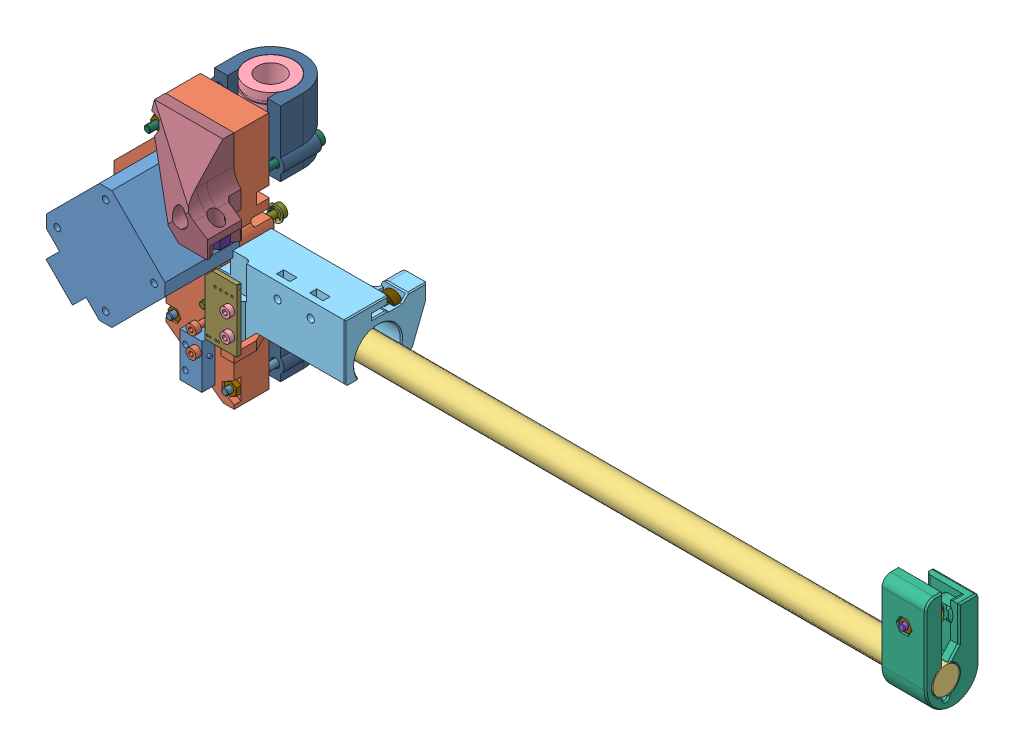
SolidWorks assembly 760, configuration Default. Lengths in mm.
Overall size (372.85 108.5 80.25).
66 component instances, 29 part files, 180 mates.
Components (placement in the parent):
- 561-1: 561 [Default] at (0 0 -40.5115) size (374.33 108.5 5) (hidden)
- 408-1: 408 [Default] at (0 0 14.2385) x (0.707107 0.707107 0) z (0 0 -1) size (50.7 42 57.75)
- 473-1: 473 [Default] at (0 0 -35.5115) size (60.5 108.5 22)
- 402-1: 402 [Default] at (337 -20 -29.4615) x (0 0.998575 0.053361) z (-1 0 0) size (12 12 350)
- 444-1: 444 [Default] at (9.5 13.5 -51.0115) x (0.980494 0 -0.196548) z (0 1 0) size (21 21 30)
- 444-2: 444 [Default] at (9.5 -65 -51.0115) x (0.998608 0 0.052748) z (0 1 0) size (21 21 30)
- 546-1: 546 [Default] at (56.7076 -20 -29.4615) x (0 0 -1) z (0 1 0) size (38 60 36)
- 462-1: 462 [Default] at (337 -20 -29.4615) x (0 -1 0) z (-1 0 0) size (47 24 20)
- 279-1: 279 [Default] at (326.1205 1.9151 -31.2115) x (0.586338 -0.810066 0) z (0 0 1) size (10 10 4)
- 562-1: 562 [Default] at (317 10 -27.9115) x (1 0 0) z (0 1 0) size (319.5 28 5) (hidden)
- 468-1: 468 [Default] at (327 0.7 -42.6615) x (-0.768982 0.639271 0) z (0 0 -1) size (6.75 6.75 25)
- 258-1: 258 [Default] at (327 0.7 -23.4615) x (0.5 -0.866025 0) z (0 0 1) size (6.35 5.5 2.4)
- 279-2: 279 [Default] at (63.5 12.093 -35.0678) x (0 0.271304 -0.962494) z (-1 0 0) size (10 10 4) (hidden)
- 257-1: 257 [Default] at (62 12.5 -36.5115) x (0 -0.745678 0.666307) z (-1 0 0) size (5.7 5.7 15) (hidden)
- 258-2: 258 [Default] at (73.9 12.5 -36.5115) x (0 1 0) z (-1 0 0) size (6.35 5.5 2.4) (hidden)
- 407-1: 407 [Default] at (88.5 12.5 -66.5115) x (0 0 1) z (-1 0 0) size (39.3 20.5 20) (hidden)
- 279-3: 279 [Default] at (63.5 13.116 -67.8792) x (0 -0.41064 0.911797) z (-1 0 0) size (10 10 4) (hidden)
- 492-1: 492 [Default] at (9.5 13.5 -51.0115) x (1 0 0) z (0 1 0) size (33.1 25.5 30)
- 241-1: 241 [Default] at (62 12.5 -66.5115) x (0 0.346036 0.938221) z (-1 0 0) size (5.7 5.7 23) (hidden)
- 258-3: 258 [Default] at (78.9 12.5 -66.5115) x (0 0 1) z (-1 0 0) size (6.35 5.5 2.4) (hidden)
- 443-1: 443 [Default] at (57.7076 -20 -29.4615) x (0 0.269578 -0.962978) z (-1 0 0) size (21 21 57) (hidden)
- 1095-1: 1095 [Default] at (24.2076 -32.9 -17.93) x (-1 0 0) z (0 -1 0) size (7 7.7 2.5)
- 545-1: 545 [Default] at (26.4299 -22.001 -13.4615) size (14.35 28.32 1.85)
- 467-1: 467 [Default] at (84.5 12.5 -44.7865) x (-1 0 0) z (0 0 -1) size (6.75 6.75 20) (hidden)
- 258-4: 258 [Default] at (84.5 12.5 -30.0115) x (0.866025 0.5 0) z (0 0 1) size (6.35 5.5 2.4) (hidden)
- 258-5: 258 [Default] at (72.5 20.1 -46.9115) x (0.866025 -0.5 0) z (0 0 1) size (6.35 5.5 2.4) (hidden)
- 258-6: 258 [Default] at (-10.5 -27.55 -22.5115) x (-0.5 -0.866025 0) z (0 0 1) size (6.35 5.5 2.4)
- 258-7: 258 [Default] at (14 -27.55 -20.1115) x (0 1 0) z (0 0 -1) size (6.35 5.5 2.4)
- 492-2: 492 [Default] at (9.5 -65 -51.0115) x (1 0 0) z (0 1 0) size (33.1 25.5 30)
- 425-1: 425 [Default] at (9.4 28.5 -19.5115) size (41.5 33.5 22.5)
- 258-8: 258 [Default] at (-3.05 -41.5 -22.5115) x (-0.5 0.866025 0) z (0 0 1) size (6.35 5.5 2.4)
- 258-9: 258 [Default] at (22.05 -58.5 -22.5115) x (-0.866025 -0.5 0) z (0 0 1) size (6.35 5.5 2.4)
- 257-2: 257 [Default] at (72.5 20.1 -35.5115) x (0.768982 -0.639271 0) z (0 0 1) size (5.7 5.7 15) (hidden)
- 380-1: 380 [Default] at (-3.05 -41.5 -57.5115) x (-0.955202 0.295955 0) z (0 0 -1) size (5.7 5.7 43)
- 380-2: 380 [Default] at (22.05 -58.5 -57.5115) x (-0.955202 0.295955 0) z (0 0 -1) size (5.7 5.7 43)
- 465-1: 465 [Default] at (-3.05 37 -57.5115) x (-0.955202 0.295955 0) z (0 0 -1) size (5.7 5.7 53)
- 465-2: 465 [Default] at (22.05 20 -57.5115) x (-0.955202 0.295955 0) z (0 0 -1) size (5.7 5.7 53)
- 112-1: 112 [Default] at (14 -27.55 -40.5115) x (-0.979655 0.200688 0) z (0 0 -1) size (5.7 5.7 28)
- 112-2: 112 [Default] at (-10.5 -27.55 -40.5115) x (-0.212871 0.97708 0) z (0 0 -1) size (5.7 5.7 28)
- 112-3: 112 [Default] at (-21.9203 0 -40.5115) x (-0.212871 0.97708 0) z (0 0 -1) size (5.7 5.7 28)
- 112-4: 112 [Default] at (21.9203 0 -40.5115) x (-0.212871 0.97708 0) z (0 0 -1) size (5.7 5.7 28)
- 712-1: 712 [Default] at (30.9 15 -5.0115) x (-0.866025 0 0.5) z (0 -1 0) size (9.24 8 4)
- 423-1: 423 [Default] at (73.8076 -9.1 -39.9615) x (0.999989 -0.00466 0) z (0 0 1) size (9 9 4)
- 185-1: 185 [Default] at (11.3 -49.2666 -13.1115) x (0 1 0) z (0 0 -1) size (20 11 6)
- 461-1: 461 [Default] at (13.8 -44.1666 -13.1115) x (-0.990362 0.138502 0) z (0 0 1) size (4.5 4.5 12.5)
- 461-2: 461 [Default] at (13.8 -34.6666 -13.1115) x (-0.990362 0.138502 0) z (0 0 1) size (4.5 4.5 12.5)
- 212-2: 212 [Default] at (21.9203 0 -41.0115) x (0.714664 -0.699468 0) z (0 0 1) size (7 7 0.5)
- 212-3: 212 [Default] at (-21.9203 0 -40.5115) x (-0.921174 0.38915 0) z (0 0 -1) size (7 7 0.5)
- 258-10: 258 [Default] at (22.05 20 -12.1115) x (0 1 0) z (0 0 -1) size (6.35 5.5 2.4)
- 258-11: 258 [Default] at (-3.05 37 -12.1115) x (-0.5 0.866025 0) z (0 0 -1) size (6.35 5.5 2.4)
- 212-4: 212 [Default] at (68 12.5 -66.5115) x (0 0 1) z (-1 0 0) size (7 7 0.5) (hidden)
- 212-5: 212 [Default] at (66.5 12.5 -66.5115) x (0 -0.383049 0.923728) z (-1 0 0) size (7 7 0.5) (hidden)
- 212-6: 212 [Default] at (67.5 12.5 -66.5115) x (0 -0.383049 0.923728) z (-1 0 0) size (7 7 0.5) (hidden)
- 212-7: 212 [Default] at (66.5 12.5 -66.5115) x (0 0 -1) z (1 0 0) size (7 7 0.5) (hidden)
- 212-8: 212 [Default] at (68.5 12.5 -66.5115) x (0 0 1) z (-1 0 0) size (7 7 0.5) (hidden)
- 212-9: 212 [Default] at (66 12.5 -36.5115) x (0 -0.976045 -0.21757) z (1 0 0) size (7 7 0.5) (hidden)
- 212-10: 212 [Default] at (68 12.5 -36.5115) x (0 -0.924225 -0.381849) z (1 0 0) size (7 7 0.5) (hidden)
- 212-11: 212 [Default] at (67.5 12.5 -36.5115) x (0 0.066998 0.997753) z (-1 0 0) size (7 7 0.5) (hidden)
- 212-12: 212 [Default] at (67 12.5 -36.5115) x (0 0.177642 0.984095) z (-1 0 0) size (7 7 0.5) (hidden)
- 212-13: 212 [Default] at (68 12.5 -36.5115) x (0 0 1) z (-1 0 0) size (7 7 0.5) (hidden)
- 258-12: 258 [Default] at (49.2076 -7 -19.6615) x (0.866025 -0.5 0) z (0 0 1) size (6.35 5.5 2.4)
- 258-14: 258 [Default] at (64.2076 -7 -17.2615) x (-0.866025 -0.5 0) z (0 0 -1) size (6.35 5.5 2.4)
- 110-1: 110 [Default] at (30.4076 -19 -11.8615) size (4.5 4.5 7.5)
- 110-2: 110 [Default] at (30.4076 -29 -11.8615) size (4.5 4.5 7.5)
- 257-4: 257 [Default] at (73.8076 -9.1 -48.4615) x (-0.923728 -0.383049 0) z (0 0 -1) size (5.7 5.7 15)
- 258-15: 258 [Default] at (73.8076 -9.1 -38.4615) x (0.866025 -0.5 0) z (0 0 1) size (6.35 5.5 2.4)
Mates (geometry in assembly coordinates):
- Coincident4: coincident anti-aligned: plane of 561-1 through (327 0.7 -35.5115) normal (0 0 1); plane of 473-1 through (21.9203 0 -35.5115) normal (0 0 -1)
- Concentric3: concentric aligned: cylinder of 561-1 through (21.9203 0 -35.5115) axis (0 0 -1) radius 1.5; cylinder of 473-1 through (21.9203 0 -19.5115) axis (0 0 -1) radius 1.65
- Parallel6: parallel anti-aligned: plane of 561-1 through (327 0.7 -40.5115) normal (0 0 -1); plane of 462-1 through (357.8396 6.7 -40.4615) normal (0 0 1)
- Coincident31: coincident anti-aligned: plane of 561-1 through (333 6.7 -35.5115) normal (1 0 0); plane of 462-1 through (333 -20 -32.4615) normal (-1 0 0)
- Coincident32: coincident anti-aligned: plane of 561-1 through (327 0.7 -35.5115) normal (0 0 1); plane of 562-1 through (312.75 15 -35.5115) normal (0 0 -1)
- Coincident202: coincident aligned: plane of 561-1 through (310 43.5 -35.5115) normal (0 1 0); plane of ? through (119.05 43.5 -28.8346) normal (0 1 0)
- Coincident80: coincident anti-aligned: plane of 561-1 through (327 0.7 -40.5115) normal (0 0 -1); plane of ? through (119.05 35.5225 -40.5115) normal (0 0 1)
- Coincident82: coincident anti-aligned: plane of 561-1 through (327 0.7 -40.5115) normal (0 0 -1); plane of ? through (177.8 35.5225 -40.5115) normal (0 0 1)
- Coincident84: coincident anti-aligned: plane of 561-1 through (327 0.7 -40.5115) normal (0 0 -1); plane of ? through (236.55 35.5225 -40.5115) normal (0 0 1)
- Coincident102: coincident anti-aligned: plane of 561-1 through (327 0.7 -40.5115) normal (0 0 -1); plane of 407-1 through (68.5 25 -40.5115) normal (0 0 1)
- Concentric89: concentric anti-aligned: cylinder of 561-1 through (72.5 20.1 -35.5115) axis (0 0 -1) radius 1.55; cylinder of 407-1 through (72.5 20.1 -71.1615) axis (0 0 1) radius 1.65
- Parallel23: parallel anti-aligned: plane of 561-1 through (327 0.7 -40.5115) normal (0 0 -1); plane of 492-1 through (18.5 43.5 -40.5115) normal (0 0 1)
- Coincident184: coincident aligned: plane of 561-1 through (310 43.5 -35.5115) normal (0 1 0); plane of 444-1 through (15.383 43.5 -52.1908) normal (0 1 0)
- Coincident193: coincident anti-aligned: plane of 561-1 through (327 0.7 -40.5115) normal (0 0 -1); plane of 492-2 through (18.5 -35 -40.5115) normal (0 0 1)
- Concentric136: concentric anti-aligned: cylinder of 561-1 through (22.05 -58.5 -35.5115) axis (0 0 -1) radius 1.55; cylinder of 492-2 through (22.05 -58.5 -66.0115) axis (0 0 1) radius 2
- Concentric178: concentric anti-aligned: cylinder of 561-1 through (72.5 20.1 -35.5115) axis (0 0 -1) radius 1.55; cylinder of 257-2 through (72.5 20.1 -47.5115) axis (0 0 1) radius 1.5
- Coincident241: coincident anti-aligned: plane of 561-1 through (327 0.7 -35.5115) normal (0 0 1); plane of 257-2 through (72.5 20.1 -35.5115) normal (0 0 -1)
- Concentric183: concentric aligned: cylinder of 561-1 through (14 -27.55 -35.5115) axis (0 0 -1) radius 1.55; cylinder of 112-1 through (14 -27.55 -15.5115) axis (0 0 -1) radius 1.5
- Coincident246: coincident anti-aligned: plane of 561-1 through (327 0.7 -40.5115) normal (0 0 -1); plane of 112-1 through (14 -27.55 -40.5115) normal (0 0 1)
- Concentric184: concentric aligned: cylinder of 561-1 through (-10.5 -27.55 -35.5115) axis (0 0 -1) radius 1.55; cylinder of 112-2 through (-10.5 -27.55 -15.5115) axis (0 0 -1) radius 1.5
- Coincident247: coincident anti-aligned: plane of 561-1 through (327 0.7 -40.5115) normal (0 0 -1); plane of 112-2 through (-10.5 -27.55 -40.5115) normal (0 0 1)
- Coincident248: coincident anti-aligned: plane of 561-1 through (327 0.7 -40.5115) normal (0 0 -1); plane of 112-3 through (-21.9203 0 -40.5115) normal (0 0 1)
- Coincident249: coincident anti-aligned: plane of 561-1 through (327 0.7 -40.5115) normal (0 0 -1); plane of 112-4 through (21.9203 0 -40.5115) normal (0 0 1)
- Coincident309: coincident anti-aligned: plane of 561-1 through (327 0.7 -40.5115) normal (0 0 -1); plane of 212-3 through (-21.9203 0 -40.5115) normal (0 0 1)
- Coincident310: coincident anti-aligned: plane of 561-1 through (327 0.7 -40.5115) normal (0 0 -1); plane of 212-2 through (21.9203 0 -40.5115) normal (0 0 1)
- Concentric120: concentric anti-aligned: cylinder of 408-1 through (0 0 -21.5115) axis (0 0 1) radius 11; cylinder of 473-1 through (0 0 -19.5115) axis (0 0 -1) radius 8
- Coincident183: coincident anti-aligned: plane of 408-1 through (0 0 -19.5115) normal (0 0 -1); plane of 473-1 through (21.9203 0 -19.5115) normal (0 0 1)
- Concentric121: concentric anti-aligned: cylinder of 408-1 through (-21.9203 0 9.2385) axis (0 0 1) radius 1.5; cylinder of 473-1 through (-21.9203 0 -19.5115) axis (0 0 -1) radius 1.65
- Concentric185: concentric aligned: cylinder of 408-1 through (21.9203 0 -14.5115) axis (0 0 -1) radius 1.5; cylinder of 112-4 through (21.9203 0 -15.5115) axis (0 0 -1) radius 1.5
- Concentric186: concentric aligned: cylinder of 408-1 through (-21.9203 0 -14.5115) axis (0 0 -1) radius 1.5; cylinder of 112-3 through (-21.9203 0 -15.5115) axis (0 0 -1) radius 1.5
- Coincident186: coincident anti-aligned: plane of 473-1 through (0 0 -22.5115) normal (0 0 1); plane of 258-6 through (-10.5 -27.55 -22.5115) normal (0 0 -1)
- Parallel24: parallel anti-aligned: plane of 258-6 through (-8.9123 -30.3 -20.1115) normal (0.866025 -0.5 0); plane of 473-1 through (-8.6834 -30.35 -22.5115) normal (-0.866025 0.5 0)
- Concentric123: concentric aligned: cylinder of 112-2 through (-10.5 -27.55 -15.5115) axis (0 0 -1) radius 1.5; cylinder of 258-6 through (-10.5 -27.55 -20.1115) axis (0 0 -1) radius 1.25
- Parallel25: parallel anti-aligned: plane of 473-1 through (16.8 -29.1666 -22.5115) normal (-1 0 0); plane of 258-7 through (16.75 -25.9623 -22.5115) normal (1 0 0)
- Concentric124: concentric anti-aligned: cylinder of 112-1 through (14 -27.55 -15.5115) axis (0 0 -1) radius 1.5; cylinder of 258-7 through (14 -27.55 -22.5115) axis (0 0 1) radius 1.25
- Coincident188: coincident anti-aligned: plane of 473-1 through (0 0 -22.5115) normal (0 0 1); plane of 258-7 through (14 -27.55 -22.5115) normal (0 0 -1)
- Coincident198: coincident anti-aligned: plane of 473-1 through (21.9203 0 -19.5115) normal (0 0 1); plane of 425-1 through (-3.25 37 -19.5115) normal (0 0 -1)
- Concentric137: concentric aligned: cylinder of 465-1 through (-3.05 37 -7.5115) axis (0 0 -1) radius 1.5; cylinder of 425-1 through (-3.05 37 2.9885) axis (0 0 -1) radius 1.65
- Concentric140: concentric aligned: cylinder of 473-1 through (22.05 20 -19.5115) axis (0 0 -1) radius 1.65; cylinder of 425-1 through (22.05 20 2.9885) axis (0 0 -1) radius 1.65
- Coincident200: coincident anti-aligned: plane of 473-1 through (0 0 -22.5115) normal (0 0 1); plane of 258-8 through (-3.05 -41.5 -22.5115) normal (0 0 -1)
- Coincident201: coincident anti-aligned: plane of 473-1 through (0 0 -22.5115) normal (0 0 1); plane of 258-9 through (22.05 -58.5 -22.5115) normal (0 0 -1)
- Parallel27: parallel anti-aligned: plane of 473-1 through (0.3832 -41.5 -22.5115) normal (-0.866025 -0.5 0); plane of 258-8 through (0.1254 -41.5 -20.1115) normal (0.866025 0.5 0)
- Concentric144: concentric aligned: cylinder of 380-1 through (-3.05 -41.5 -17.5115) axis (0 0 -1) radius 1.5; cylinder of 258-8 through (-3.05 -41.5 -20.1115) axis (0 0 -1) radius 1.25
- Parallel28: parallel anti-aligned: plane of 473-1 through (24.65 -53.6503 -22.5115) normal (0.5 -0.866025 0); plane of 258-9 through (22.05 -55.3246 -20.1115) normal (-0.5 0.866025 0)
- Concentric145: concentric aligned: cylinder of 380-2 through (22.05 -58.5 -17.5115) axis (0 0 -1) radius 1.5; cylinder of 258-9 through (22.05 -58.5 -20.1115) axis (0 0 -1) radius 1.25
- Coincident229: coincident anti-aligned: plane of 473-1 through (18.5 15 -35.5115) normal (0 -1 0); plane of 562-1 through (95.2005 15 -6.5115) normal (0 1 0)
- Concentric14: concentric anti-aligned: cylinder of 402-1 through (-13 -20 -29.4615) axis (1 0 0) radius 6; cylinder of 546-1 through (79.7076 -20 -29.4615) axis (-1 0 0) radius 10.6
- Concentric15: concentric aligned: cylinder of 402-1 through (-13 -20 -29.4615) axis (1 0 0) radius 6; cylinder of 462-1 through (317 -20 -29.4615) axis (1 0 0) radius 6.05
- Concentric98: concentric anti-aligned: cylinder of 402-1 through (-13 -20 -29.4615) axis (1 0 0) radius 6; cylinder of 443-1 through (57.7076 -20 -29.4615) axis (-1 0 0) radius 6
- Coincident195: coincident aligned: plane of 402-1 through (337 -20 -29.4615) normal (1 0 0); plane of 462-1 through (337 -20 -32.4615) normal (1 0 0)
- Concentric122: concentric aligned: cylinder of 444-1 through (9.5 13.5 -51.0115) axis (0 1 0) radius 10.5; cylinder of 492-1 through (9.5 13.5 -51.0115) axis (0 1 0) radius 10.6
- Coincident185: coincident aligned: plane of 444-1 through (15.383 43.5 -52.1908) normal (0 1 0); plane of 492-1 through (9.5 43.5 -51.0115) normal (0 1 0)
- Concentric125: concentric aligned: cylinder of 444-2 through (9.5 -65 -51.0115) axis (0 1 0) radius 10.5; cylinder of 492-2 through (9.5 -65 -51.0115) axis (0 1 0) radius 10.6
- Coincident194: coincident aligned: plane of 444-2 through (19.9854 -65 -50.4577) normal (0 -1 0); plane of 492-2 through (9.5 -65 -51.0115) normal (0 -1 0)
- Coincident156: coincident aligned: plane of 546-1 through (79.7076 -20 -29.4615) normal (1 0 0); plane of 443-1 through (79.7076 -17.1694 -39.5728) normal (1 0 0)
- Distance26: distance = 0.6 mm aligned: plane of 1095-1 through (24.2076 -35.4 -17.93) normal (0 -1 0); plane of 546-1 through (79.7076 -36 -14.4615) normal (0 -1 0)
- Distance27: distance = 0.2 mm anti-aligned: plane of 546-1 through (27.9076 -32 -13.4615) normal (-1 0 0); plane of 1095-1 through (27.7076 -35.4 -15.93) normal (1 0 0)
- Coincident206: coincident anti-aligned: plane of 546-1 through (81.0701 0 -14.4615) normal (0 0 1); plane of ? through (51.5701 -7 -14.4615) normal (0 0 -1)
- Concentric151: concentric anti-aligned: cylinder of 546-1 through (51.5701 -7 -24.4615) axis (0 0 1) radius 1.65; cylinder of ? through (51.5701 -7 -13.8615) axis (0 0 -1) radius 1.5
- Coincident207: coincident anti-aligned: plane of 546-1 through (81.0701 0 -14.4615) normal (0 0 1); plane of ? through (66.5701 -7 -14.4615) normal (0 0 -1)
- Concentric152: concentric anti-aligned: cylinder of 546-1 through (66.5701 -7 -24.4615) axis (0 0 1) radius 1.65; cylinder of ? through (66.5701 -7 -13.8615) axis (0 0 -1) radius 1.5
- Concentric16: concentric anti-aligned: cylinder of 462-1 through (327 0.7 -44.4615) axis (0 0 1) radius 1.65; cylinder of 279-1 through (327 0.7 -28.7115) axis (0 0 -1) radius 1.5
- Coincident33: coincident anti-aligned: plane of 462-1 through (317 -20 -32.4615) normal (-1 0 0); plane of 562-1 through (317 15 -27.9115) normal (1 0 0)
- Concentric26: concentric anti-aligned: cylinder of 462-1 through (327 0.7 -44.4615) axis (0 0 1) radius 1.65; cylinder of 468-1 through (327 0.7 -19.3115) axis (0 0 -1) radius 1.5
- Coincident66: coincident aligned: cone of 462-1 through (327 0.7 -44.4615) axis (0 0 1); cone of 468-1 through (327 0.7 -44.3115) axis (0 0 1)
- Coincident67: coincident anti-aligned: plane of 462-1 through (317 -20 -23.4615) normal (0 0 1); plane of 258-1 through (327 0.7 -23.4615) normal (0 0 -1)
- Coincident203: coincident anti-aligned: plane of 462-1 through (327 0.7 -33.7115) normal (0 0 1); plane of 279-1 through (327.8795 -0.5151 -33.7115) normal (0 0 -1)
- Parallel29: parallel anti-aligned: plane of 462-1 through (328.5877 3.45 -52.8629) normal (0 -1 0); plane of 258-1 through (328.5877 3.45 -21.0615) normal (0 1 0)
- Parallel21: parallel anti-aligned: plane of 562-1 through (81.75 15 -30.0115) normal (1 0 0); plane of 258-4 through (81.75 14.0877 -27.6115) normal (-1 0 0)
- Coincident179: coincident aligned: plane of 562-1 through (81 15 -30.0115) normal (0 0 -1); plane of 258-4 through (84.5 12.5 -30.0115) normal (0 0 -1)
- Parallel33: parallel anti-aligned: plane of 712-1 through (26.9 11 -2.7021) normal (-1 0 0); plane of 425-1 through (26.8 10 -7.3787) normal (1 0 0)
- Concentric28: concentric aligned: cylinder of 468-1 through (327 0.7 -19.3115) axis (0 0 -1) radius 1.5; cylinder of 258-1 through (327 0.7 -21.0615) axis (0 0 -1) radius 1.25
- Coincident81: coincident aligned: plane of ? through (119.05 43.5 -28.8346) normal (0 1 0); plane of ? through (177.8 43.5 -28.8346) normal (0 1 0)
- Coincident83: coincident aligned: plane of ? through (177.8 43.5 -28.8346) normal (0 1 0); plane of ? through (236.55 43.5 -28.8346) normal (0 1 0)
- Concentric50: concentric anti-aligned: cylinder of 279-2 through (61 12.5 -36.5115) axis (1 0 0) radius 1.5; cylinder of 257-1 through (74 12.5 -36.5115) axis (-1 0 0) radius 1.5
- Coincident93: coincident anti-aligned: plane of 279-2 through (62 13.1104 -38.6771) normal (-1 0 0); plane of 257-1 through (62 12.5 -36.5115) normal (1 0 0)
- Concentric53: concentric anti-aligned: cylinder of 257-1 through (74 12.5 -36.5115) axis (-1 0 0) radius 1.5; cylinder of 258-2 through (71.5 12.5 -36.5115) axis (1 0 0) radius 1.25
- Concentric87: concentric anti-aligned: cylinder of 257-1 through (74 12.5 -36.5115) axis (-1 0 0) radius 1.5; cylinder of 407-1 through (68.5 12.5 -36.5115) axis (1 0 0) radius 1.65
- Parallel14: parallel anti-aligned: plane of 258-2 through (71.5 10.9123 -33.7615) normal (0 0 1); plane of 407-1 through (71.5 14.1166 -33.7115) normal (0 0 -1)
- Coincident150: coincident anti-aligned: plane of 258-2 through (71.5 12.5 -36.5115) normal (-1 0 0); plane of 407-1 through (71.5 12.5 -66.5115) normal (1 0 0)
- Concentric91: concentric anti-aligned: cylinder of 407-1 through (68.5 12.5 -66.5115) axis (1 0 0) radius 1.65; cylinder of 241-1 through (82 12.5 -66.5115) axis (-1 0 0) radius 1.5
- Coincident153: coincident anti-aligned: plane of 407-1 through (76.5 12.5 -66.5115) normal (1 0 0); plane of 258-3 through (76.5 12.5 -66.5115) normal (-1 0 0)
- Parallel15: parallel anti-aligned: plane of 407-1 through (76.5 12.5 -63.3361) normal (0 0.5 -0.866025); plane of 258-3 through (76.5 9.75 -64.9238) normal (0 -0.5 0.866025)
- Coincident178: coincident: cone of 407-1 through (84.5 12.5 -46.5115) axis (0 0 1); circle of 467-1
- Concentric117: concentric anti-aligned: cylinder of 407-1 through (72.5 20.1 -71.1615) axis (0 0 1) radius 1.65; cylinder of 258-5 through (72.5 20.1 -44.5115) axis (0 0 -1) radius 1.25
- Parallel22: parallel anti-aligned: plane of 407-1 through (68.5 19.2917 -92.9104) normal (0.5 0.866025 0); plane of 258-5 through (69.75 18.5123 -44.5115) normal (-0.5 -0.866025 0)
- Coincident182: coincident anti-aligned: plane of 407-1 through (88.5 12.5 -44.5115) normal (0 0 -1); plane of 258-5 through (72.5 20.1 -44.5115) normal (0 0 1)
- Concentric181: concentric anti-aligned: cylinder of 492-1 through (22.05 20 -66.0115) axis (0 0 1) radius 2; cylinder of 465-2 through (22.05 20 -7.5115) axis (0 0 -1) radius 1.5
- Concentric182: concentric anti-aligned: cylinder of 492-1 through (-3.05 37 -66.0115) axis (0 0 1) radius 2; cylinder of 465-1 through (-3.05 37 -7.5115) axis (0 0 -1) radius 1.5
- Coincident244: coincident anti-aligned: plane of 492-1 through (22.05 20 -57.5115) normal (0 0 -1); plane of 465-2 through (22.05 20 -57.5115) normal (0 0 1)
- Coincident245: coincident anti-aligned: plane of 492-1 through (-3.05 37 -57.5115) normal (0 0 -1); plane of 465-1 through (-3.05 37 -57.5115) normal (0 0 1)
- Concentric92: concentric anti-aligned: cylinder of 241-1 through (82 12.5 -66.5115) axis (-1 0 0) radius 1.5; cylinder of 258-3 through (76.5 12.5 -66.5115) axis (1 0 0) radius 1.25
- Concentric116: concentric aligned: cylinder of 467-1 through (84.5 12.5 -26.4365) axis (0 0 -1) radius 1.5; cylinder of 258-4 through (84.5 12.5 -27.6115) axis (0 0 -1) radius 1.25
- Concentric179: concentric anti-aligned: cylinder of 492-2 through (-3.05 -41.5 -66.0115) axis (0 0 1) radius 2; cylinder of 380-1 through (-3.05 -41.5 -17.5115) axis (0 0 -1) radius 1.5
- Coincident242: coincident anti-aligned: plane of 492-2 through (-3.05 -41.5 -57.5115) normal (0 0 -1); plane of 380-1 through (-3.05 -41.5 -57.5115) normal (0 0 1)
- Concentric180: concentric anti-aligned: cylinder of 492-2 through (22.05 -58.5 -66.0115) axis (0 0 1) radius 2; cylinder of 380-2 through (22.05 -58.5 -17.5115) axis (0 0 -1) radius 1.5
- Coincident243: coincident anti-aligned: plane of 492-2 through (22.05 -58.5 -57.5115) normal (0 0 -1); plane of 380-2 through (22.05 -58.5 -57.5115) normal (0 0 1)
- Coincident251: coincident anti-aligned: plane of 425-1 through (34.9 15 2.9885) normal (0 -1 0); plane of 712-1 through (30.9 15 -5.0115) normal (0 1 0)
- Coincident311: coincident anti-aligned: plane of 425-1 through (9.4 28.5 -14.5115) normal (0 0 1); plane of 258-10 through (22.05 20 -14.5115) normal (0 0 -1)
- Parallel39: parallel anti-aligned: plane of 425-1 through (24.8 18.4123 -1.5115) normal (-1 0 0); plane of 258-10 through (24.8 21.5877 -14.5115) normal (1 0 0)
- Coincident312: coincident anti-aligned: plane of 425-1 through (9.4 28.5 -14.5115) normal (0 0 1); plane of 258-11 through (-3.05 37 -14.5115) normal (0 0 -1)
- Parallel40: parallel aligned: plane of 425-1 through (-1.9781 33.7029 -1.5115) normal (-0.866025 0.5 0); plane of 258-11 through (-6.2254 37 -14.5115) normal (-0.866025 0.5 0)
- Concentric260: concentric anti-aligned: cylinder of 465-1 through (-3.05 37 -7.5115) axis (0 0 -1) radius 1.5; cylinder of 258-11 through (-3.05 37 -14.5115) axis (0 0 1) radius 1.25
- Concentric259: concentric anti-aligned: cylinder of 465-2 through (22.05 20 -7.5115) axis (0 0 -1) radius 1.5; cylinder of 258-10 through (22.05 20 -14.5115) axis (0 0 1) radius 1.25
- Concentric257: concentric anti-aligned: cylinder of 112-3 through (-21.9203 0 -15.5115) axis (0 0 -1) radius 1.5; cylinder of 212-3 through (-21.9203 0 -41.0115) axis (0 0 1) radius 1.6
- Concentric258: concentric aligned: cylinder of 112-4 through (21.9203 0 -15.5115) axis (0 0 -1) radius 1.5; cylinder of 212-2 through (21.9203 0 -40.5115) axis (0 0 -1) radius 1.6
- Concentric100: concentric anti-aligned: cylinder of ? through (233.7392 0 -9.9615) axis (0 -1 0) radius 2.5; cylinder of ? through (233.7392 -15.1 -9.9615) axis (0 1 0) radius 2.5
- Concentric101: concentric anti-aligned: cylinder of ? through (207.7392 0 -9.9615) axis (0 -1 0) radius 2.5; cylinder of ? through (207.7392 -15.1 -9.9615) axis (0 1 0) radius 2.5
- Parallel17: parallel aligned: plane of ? through (200.5392 0 -3.9615) normal (0 0 1); plane of ? through (230.7392 -26.5 1.0385) normal (0 0 1)
- Distance39: distance = 0.5 mm anti-aligned: plane of ? through (240.9392 0 -13.9615) normal (0 0 -1); plane of 546-1 through (240.7392 0 -14.4615) normal (0 0 1)
- Concentric278: concentric: cylinder of 546-1 through (213.2392 -7 -24.4615) axis (0 0 1) radius 1.55; cylinder of ? through (213.2392 -7 -13.9615) axis (0 0 1) radius 1.55
- Concentric279: concentric aligned: cylinder of 546-1 through (228.2392 -7 -24.4615) axis (0 0 1) radius 1.55; cylinder of ? through (228.2392 -7 -13.9615) axis (0 0 1) radius 1.55
- Concentric103: concentric anti-aligned: cylinder of ? through (233.7392 -15.1 -9.9615) axis (0 1 0) radius 2; cylinder of ? through (233.7392 -26.5 -9.9615) axis (0 -1 0) radius 1.65
- Coincident161: coincident anti-aligned: plane of ? through (235.7392 -26.5 -9.9615) normal (0 -1 0); plane of ? through (233.7392 -26.5 -9.9615) normal (0 1 0)
- Concentric105: concentric anti-aligned: cylinder of ? through (207.7392 -15.1 -9.9615) axis (0 1 0) radius 2; cylinder of ? through (207.7392 -26.5 -9.9615) axis (0 -1 0) radius 1.65
- Coincident165: coincident anti-aligned: plane of ? through (209.7392 -26.5 -9.9615) normal (0 -1 0); plane of ? through (207.7392 -26.5 -9.9615) normal (0 1 0)
- Parallel44: parallel anti-aligned: plane of ? through (230.7392 -26.5 1.0385) normal (0 0 1); plane of 1095-1 through (191.7392 -35.4 -19.93) normal (0 0 -1)
- Coincident340: coincident anti-aligned: plane of 561-1 through (327 0.7 -40.5115) normal (0 0 -1); plane of 492-1 through (18.5 43.5 -40.5115) normal (0 0 1)
- Concentric280: concentric aligned: cylinder of 444-1 through (9.5 13.5 -51.0115) axis (0 1 0) radius 6; cylinder of 444-2 through (9.5 -65 -51.0115) axis (0 1 0) radius 6
- Parallel45: parallel anti-aligned: plane of 561-1 through (18.5 -4.6 -35.5115) normal (0 -1 0); plane of 407-1 through (68.5 25 -71.1615) normal (0 1 0)
- Concentric285: concentric anti-aligned: cylinder of 473-1 through (30.5 -20 -29.4615) axis (-1 0 0) radius 6.025; cylinder of 402-1 through (-13 -20 -29.4615) axis (1 0 0) radius 6
- Tangent1: tangent anti-aligned: cylinder of 423-1 through (73.8076 -9.1 -37.4615) axis (0 0 -1) radius 4.5; plane of 561-1 through (18.5 -4.6 -35.5115) normal (0 -1 0)
- Concentric290: concentric anti-aligned: cylinder of 241-1 through (82 12.5 -66.5115) axis (-1 0 0) radius 1.5; cylinder of 212-4 through (67.5 12.5 -66.5115) axis (1 0 0) radius 1.6
- Coincident350: coincident anti-aligned: plane of 212-4 through (68 12.5 -66.5115) normal (1 0 0); plane of 212-8 through (68 12.5 -66.5115) normal (-1 0 0)
- Concentric291: concentric anti-aligned: cylinder of 241-1 through (82 12.5 -66.5115) axis (-1 0 0) radius 1.5; cylinder of 212-5 through (66 12.5 -66.5115) axis (1 0 0) radius 1.6
- Concentric289: concentric anti-aligned: cylinder of 241-1 through (82 12.5 -66.5115) axis (-1 0 0) radius 1.5; cylinder of 212-6 through (67 12.5 -66.5115) axis (1 0 0) radius 1.6
- Concentric292: concentric aligned: cylinder of 241-1 through (82 12.5 -66.5115) axis (-1 0 0) radius 1.5; cylinder of 212-7 through (67 12.5 -66.5115) axis (-1 0 0) radius 1.6
- Concentric294: concentric anti-aligned: cylinder of 241-1 through (82 12.5 -66.5115) axis (-1 0 0) radius 1.5; cylinder of 212-8 through (68 12.5 -66.5115) axis (1 0 0) radius 1.6
- Coincident349: coincident anti-aligned: plane of 407-1 through (68.5 12.5 -36.5115) normal (-1 0 0); plane of 212-8 through (68.5 12.5 -66.5115) normal (1 0 0)
- Coincident351: coincident anti-aligned: plane of 212-4 through (67.5 12.5 -66.5115) normal (-1 0 0); plane of 212-6 through (67.5 12.5 -66.5115) normal (1 0 0)
- Coincident352: coincident anti-aligned: plane of 212-6 through (67 12.5 -66.5115) normal (-1 0 0); plane of 212-7 through (67 12.5 -66.5115) normal (1 0 0)
- Coincident353: coincident anti-aligned: plane of 212-5 through (66.5 12.5 -66.5115) normal (1 0 0); plane of 212-7 through (66.5 12.5 -66.5115) normal (-1 0 0)
- Concentric295: concentric anti-aligned: cylinder of 279-3 through (61 12.5 -66.5115) axis (1 0 0) radius 1.5; cylinder of 241-1 through (82 12.5 -66.5115) axis (-1 0 0) radius 1.5
- Coincident354: coincident anti-aligned: plane of 279-3 through (66 11.884 -65.1438) normal (1 0 0); plane of 212-5 through (66 12.5 -66.5115) normal (-1 0 0)
- Coincident355: coincident anti-aligned: plane of 279-3 through (62 11.5761 -64.46) normal (-1 0 0); plane of 241-1 through (62 12.5 -66.5115) normal (1 0 0)
- Concentric296: concentric aligned: cylinder of 257-1 through (74 12.5 -36.5115) axis (-1 0 0) radius 1.5; cylinder of 212-10 through (68.5 12.5 -36.5115) axis (-1 0 0) radius 1.6
- Concentric297: concentric anti-aligned: cylinder of 257-1 through (74 12.5 -36.5115) axis (-1 0 0) radius 1.5; cylinder of 212-11 through (67 12.5 -36.5115) axis (1 0 0) radius 1.6
- Concentric298: concentric anti-aligned: cylinder of 257-1 through (74 12.5 -36.5115) axis (-1 0 0) radius 1.5; cylinder of 212-12 through (66.5 12.5 -36.5115) axis (1 0 0) radius 1.6
- Concentric299: concentric anti-aligned: cylinder of 257-1 through (74 12.5 -36.5115) axis (-1 0 0) radius 1.5; cylinder of 212-13 through (67.5 12.5 -36.5115) axis (1 0 0) radius 1.6
- Concentric300: concentric aligned: cylinder of 212-9 through (66.5 12.5 -36.5115) axis (-1 0 0) radius 1.6; cylinder of 257-1 through (74 12.5 -36.5115) axis (-1 0 0) radius 1.5
- Coincident357: coincident anti-aligned: plane of 279-2 through (66 12.907 -37.9553) normal (1 0 0); plane of 212-9 through (66 12.5 -36.5115) normal (-1 0 0)
- Coincident358: coincident anti-aligned: plane of 212-9 through (66.5 12.5 -36.5115) normal (1 0 0); plane of 212-12 through (66.5 12.5 -36.5115) normal (-1 0 0)
- Coincident359: coincident anti-aligned: plane of 212-11 through (67 12.5 -36.5115) normal (-1 0 0); plane of 212-12 through (67 12.5 -36.5115) normal (1 0 0)
- Coincident360: coincident anti-aligned: plane of 212-11 through (67.5 12.5 -36.5115) normal (1 0 0); plane of 212-13 through (67.5 12.5 -36.5115) normal (-1 0 0)
- Coincident361: coincident anti-aligned: plane of 212-10 through (68 12.5 -36.5115) normal (-1 0 0); plane of 212-13 through (68 12.5 -36.5115) normal (1 0 0)
- Coincident362: coincident anti-aligned: plane of 407-1 through (68.5 12.5 -36.5115) normal (-1 0 0); plane of 212-10 through (68.5 12.5 -36.5115) normal (1 0 0)
- Concentric301: concentric anti-aligned: cylinder of 425-1 through (30.9 43.5 -5.0115) axis (0 -1 0) radius 3; cylinder of 712-1 through (30.9 11 -5.0115) axis (0 1 0) radius 2.1
- Concentric304: concentric anti-aligned: cylinder of 546-1 through (49.2076 -7 -24.4615) axis (0 0 1) radius 1.65; cylinder of 258-12 through (49.2076 -7 -17.2615) axis (0 0 -1) radius 1.25
- Concentric305: concentric aligned: cylinder of 546-1 through (64.2076 -7 -24.4615) axis (0 0 1) radius 1.65; cylinder of 258-14 through (64.2076 -7 -19.6615) axis (0 0 1) radius 1.25
- Parallel48: parallel anti-aligned: plane of 546-1 through (52.0076 1.3141 -20.4615) normal (-1 0 0); plane of 258-12 through (51.9576 -8.5877 -17.2615) normal (1 0 0)
- Parallel49: parallel anti-aligned: plane of 546-1 through (67.0076 -9.0166 -20.4615) normal (-1 0 0); plane of 258-14 through (66.9576 -5.4123 -19.6615) normal (1 0 0)
- Coincident368: coincident anti-aligned: plane of 546-1 through (56.7076 -20 -17.2615) normal (0 0 -1); plane of 258-12 through (49.2076 -7 -17.2615) normal (0 0 1)
- Coincident369: coincident anti-aligned: plane of 546-1 through (56.7076 -20 -17.2615) normal (0 0 -1); plane of 258-14 through (64.2076 -7 -17.2615) normal (0 0 1)
- Concentric306: concentric aligned: cylinder of 546-1 through (30.4076 -19 -17.4615) axis (0 0 1) radius 1.25; cylinder of 110-1 through (30.4076 -19 -16.8615) axis (0 0 1) radius 1.25
- Concentric307: concentric aligned: cylinder of 546-1 through (30.4076 -29 -17.4615) axis (0 0 1) radius 1.25; cylinder of 110-2 through (30.4076 -29 -16.8615) axis (0 0 1) radius 1.25
- Width6: width anti-aligned: plane of 561-1 through (119 43.5 -35.5115) normal (1 0 0); plane of 561-1 through (133.5 39.5 -35.5115) normal (-1 0 0); plane of ? through (119.05 65.0387 -106.5115) normal (-1 0 0); plane of ? through (133.45 65.0387 -106.5115) normal (1 0 0)
- Width7: width anti-aligned: plane of 561-1 through (177.75 43.5 -35.5115) normal (1 0 0); plane of 561-1 through (192.25 39.5 -35.5115) normal (-1 0 0); plane of ? through (177.8 65.0387 -106.5115) normal (-1 0 0); plane of ? through (192.2 65.0387 -106.5115) normal (1 0 0)
- Width8: width anti-aligned: plane of 561-1 through (236.5 43.5 -35.5115) normal (1 0 0); plane of 561-1 through (251 39.5 -35.5115) normal (-1 0 0); plane of ? through (236.55 65.0387 -106.5115) normal (-1 0 0); plane of ? through (250.95 65.0387 -106.5115) normal (1 0 0)
- Parallel50: parallel anti-aligned: plane of 562-1 through (95.2005 15 -6.5115) normal (0 1 0); plane of 425-1 through (34.9 10 -31.2711) normal (0 -1 0)
- Coincident374: coincident anti-aligned: plane of ? through (221.0205 -9.3141 53.8368) normal (0 0.866025 -0.5); plane of ? through (221.0205 -9.3141 53.8368) normal (0 -0.866025 0.5)
- Concentric314: concentric aligned: cylinder of ? through (241.5266 -19.5671 36.078) axis (0 -0.866025 0.5) radius 2.1; cylinder of ? through (241.5266 -16.103 34.078) axis (0 -0.866025 0.5) radius 2.1
- Concentric315: concentric aligned: cylinder of ? through (221.0205 -9.3141 53.8368) axis (0 -0.866025 0.5) radius 24.5; cylinder of ? through (221.0205 54.1625 17.1885) axis (0 -0.866025 0.5) radius 24.5
- Concentric317: concentric aligned: cylinder of 546-1 through (66.5701 -7 -24.4615) axis (0 0 1) radius 1.65; cylinder of ? through (66.5701 -7 -22.0365) axis (0 0 1) radius 1.5
- Concentric318: concentric aligned: cylinder of 546-1 through (51.5701 -7 -24.4615) axis (0 0 1) radius 1.65; cylinder of ? through (51.5701 -7 -22.0365) axis (0 0 1) radius 1.5
- Coincident375: coincident anti-aligned: plane of 546-1 through (81.0701 0 -14.4615) normal (0 0 1); plane of ? through (39.0701 0 -14.4615) normal (0 0 -1)
- Coincident381: coincident anti-aligned: plane of 546-1 through (73.7076 -8.2 -48.4615) normal (0 0 -1); plane of 257-4 through (73.8076 -9.1 -48.4615) normal (0 0 1)
- Concentric321: concentric aligned: cylinder of 423-1 through (73.8076 -9.1 -37.4615) axis (0 0 -1) radius 1.5; cylinder of 257-4 through (73.8076 -9.1 -36.4615) axis (0 0 -1) radius 1.5
- Concentric323: concentric aligned: cylinder of 257-4 through (73.8076 -9.1 -36.4615) axis (0 0 -1) radius 1.5; cylinder of 258-15 through (73.8076 -9.1 -36.0615) axis (0 0 -1) radius 1.25
- Coincident384: coincident anti-aligned: plane of 423-1 through (76.1701 -9.107 -42.4615) normal (0 0 -1); plane of ? through (265.9581 -9.1 -42.4615) normal (0 0 1)
- Coincident385: coincident anti-aligned: plane of 546-1 through (74.5701 -10.1 -42.9615) normal (0 0 1); plane of ? through (265.9581 -9.1 -42.9615) normal (0 0 -1)
- Coincident386: coincident: plane of 546-1 through (266.9819 0 -14.4615) normal (0 0 1); plane of ? through (226.9819 0 -14.4615) normal (0 0 -1)
- Concentric324: concentric: cylinder of 546-1 through (254.4819 -7 -24.4615) axis (0 0 1) radius 1.65; cylinder of ? through (254.4819 -7 -22.0365) axis (0 0 1) radius 1.5
- Concentric325: concentric aligned: cylinder of 546-1 through (239.4819 -7 -24.4615) axis (0 0 1) radius 1.65; cylinder of ? through (239.4819 -7 -22.0365) axis (0 0 1) radius 1.5
- Coincident387: coincident anti-aligned: plane of 546-1 through (277.8592 0 -14.4615) normal (0 0 1); plane of ? through (237.8592 0 -14.4615) normal (0 0 -1)
- Concentric326: concentric aligned: cylinder of 546-1 through (250.3592 -7 -24.4615) axis (0 0 1) radius 1.65; cylinder of ? through (250.3592 -7 -14.4615) axis (0 0 1) radius 1.65
- Concentric327: concentric aligned: cylinder of 546-1 through (265.3592 -7 -24.4615) axis (0 0 1) radius 1.65; cylinder of ? through (265.3592 -7 -14.4615) axis (0 0 1) radius 1.65
- Coincident388: coincident anti-aligned: plane of 423-1 through (76.0575 -9.1105 -38.4615) normal (0 0 1); plane of 258-15 through (73.8076 -9.1 -38.4615) normal (0 0 -1)
- Parallel51: parallel anti-aligned: plane of 546-1 through (78.7076 0 -42.9615) normal (-1 0 0); plane of 258-15 through (76.5576 -10.6877 -36.0615) normal (1 0 0)
- Tangent2: tangent anti-aligned: plane of 546-1 through (75.3076 -10.2 -13.4605) normal (-1 0 0); cylinder of 257-4 through (73.8076 -9.1 -36.4615) axis (0 0 -1) radius 1.5
- Concentric328: concentric anti-aligned: cylinder of 545-1 through (30.4076 -29 -11.6115) axis (0 0 -1) radius 1.4999; circle of 110-2
